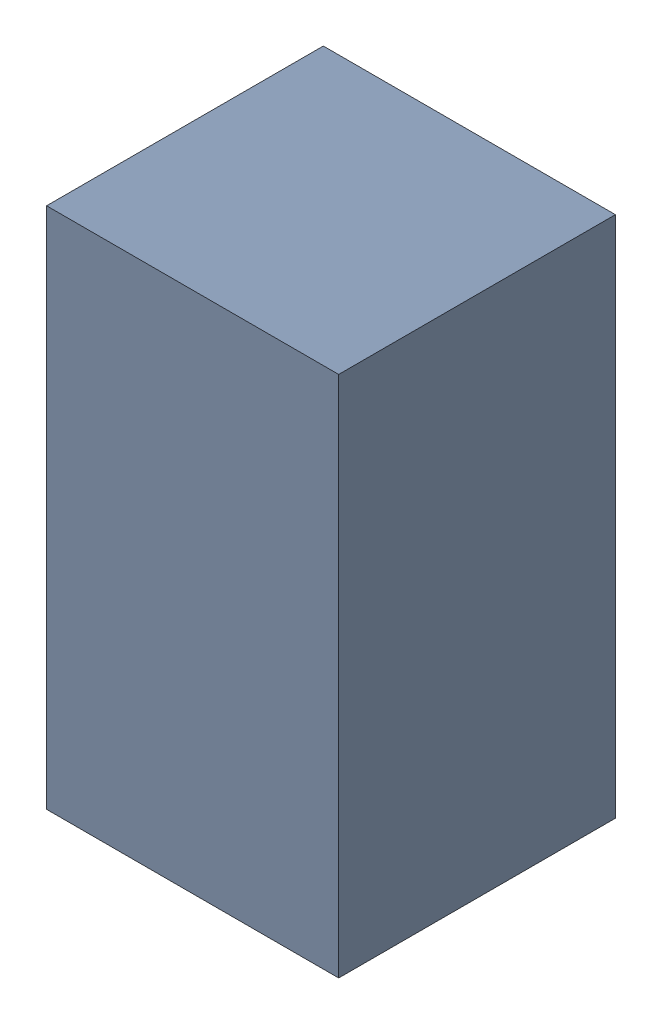
SolidWorks assembly R3_TDA4, configuration Standard. Lengths in mm.
Overall size (0.95 1.7 0.9).
2 component instances, 1 part files, 0 mates.
Components (placement in the parent):
- 885541560-1: 885541560 [Standard] at (-4.81 -53.34 0) size (0.95 1.7 0.9)
  - Extruded_16-1: Extruded_16 [Standard] at origin size (0.95 1.7 0.9)
